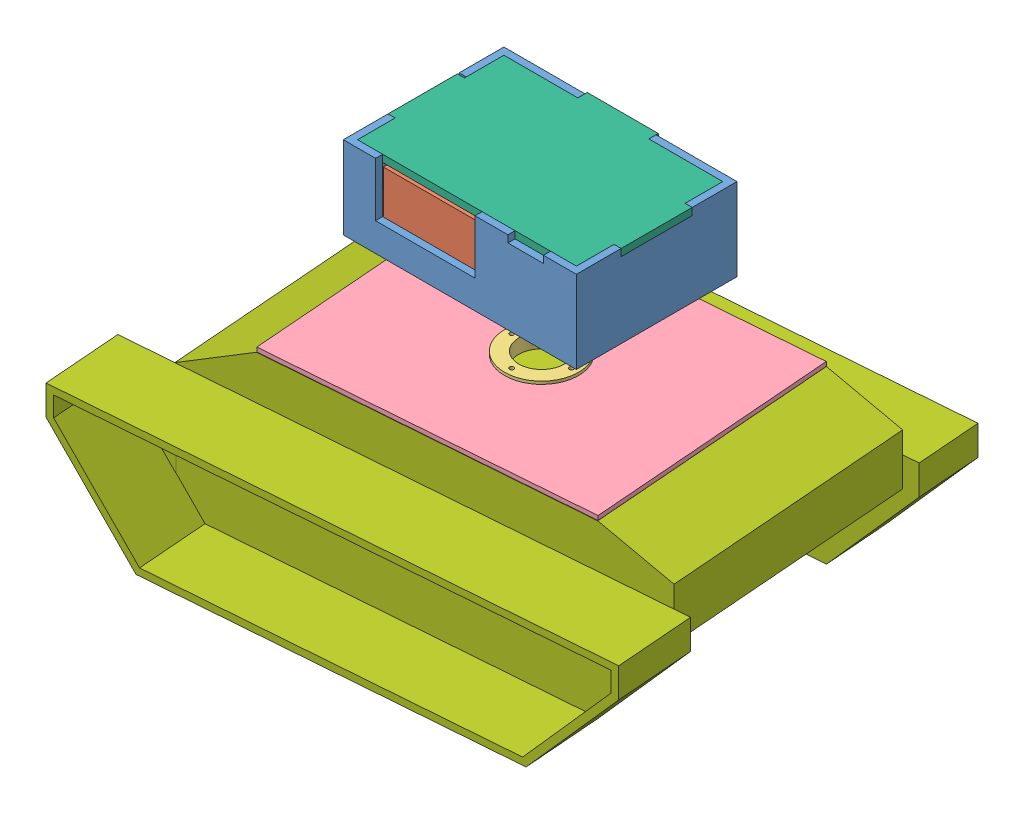
SolidWorks assembly Assemblage1, configuration Default. Lengths in mm.
Overall size (395.2 241.89 303.33).
10 component instances, 7 part files, 23 mates.
Components (placement in the parent):
- boite-1: boite [Default] at (-87.4002 206.352 80.3922) size (164 58 113)
- carte-1: carte [Default] at (-86.4002 223.352 81.6422) size (154 33 101.5)
- fixation-1: fixation [Default] at (-87.4002 137.8761 80.3922) size (70 10 70)
- plaque-1: plaque [Default] at (-87.4002 142.8761 80.3922) x (-0.07779 0 -0.99697) z (0.99697 0 -0.07779) size (174.68 3 223.37)
- entretoise-1: entretoise [Default] at (-17.4002 211.352 37.8922) x (0.957177 0 0.289503) z (-0.289503 0 0.957177) size (8 12 8)
- entretoise-2: entretoise [Default] at (-157.4002 211.352 37.8922) size (8 12 8)
- entretoise-4: entretoise [Default] at (-157.4002 211.352 125.8922) x (0.969192 0 0.246308) z (-0.246308 0 0.969192) size (8 12 8)
- entretoise-5: entretoise [Default] at (-17.4002 211.352 125.8922) x (0.714568 0 -0.699566) z (0.699566 0 0.714568) size (8 12 8)
- plexi haut-1: plexi haut [Default] at (-87.4002 259.352 81.3922) size (164 5 109.63)
- chassis-1: chassis [Default] at (-109.9498 95.7277 -5.4538) x (0.99697 0 -0.07779) z (0.07779 0 0.99697) size (374.95 120.41 275)
Mates (geometry in assembly coordinates):
- Coaxiale1: concentric aligned: cylinder of fixation-1 through (-87.4002 147.8761 80.3922) axis (0 -1 0) radius 26; cylinder of plaque-1 through (-87.4002 145.8761 80.3922) axis (0 -1 0) radius 26
- Coïncidente1: coincident anti-aligned: plane of fixation-1 through (-87.4002 142.8761 80.3922) normal (0 1 0); plane of plaque-1 through (-87.4002 142.8761 80.3922) normal (0 -1 0)
- Coaxiale2: concentric anti-aligned: cylinder of boite-1 through (-87.4002 206.352 80.3922) axis (0 1 0) radius 16; cylinder of fixation-1 through (-87.4002 147.8761 80.3922) axis (0 -1 0) radius 16
- Coïncidente2: coincident aligned: circle of boite-1; cylinder of fixation-1 through (-87.4002 112.8761 59.3922) axis (0 1 0) radius 1.5
- Parallèle1: parallel aligned: cylinder of boite-1 through (-157.4002 206.352 37.8922) axis (0 1 0) radius 1.5; cylinder of carte-1 through (-157.4002 223.352 37.8922) axis (0 1 0) radius 1.5
- Coïncidente3: coincident anti-aligned: plane of carte-1 through (-86.4002 223.352 81.6422) normal (0 -1 0); plane of entretoise-2 through (-157.4002 223.352 37.8922) normal (0 1 0)
- Coaxiale5: concentric anti-aligned: cylinder of carte-1 through (-157.4002 223.352 37.8922) axis (0 1 0) radius 1.5; cylinder of entretoise-2 through (-157.4002 223.352 37.8922) axis (0 -1 0) radius 1.5
- Coaxiale6: concentric anti-aligned: cylinder of carte-1 through (-17.4002 223.352 37.8922) axis (0 1 0) radius 1.5; cylinder of entretoise-1 through (-17.4002 223.352 37.8922) axis (0 -1 0) radius 1.5
- Coïncidente4: coincident anti-aligned: plane of carte-1 through (-86.4002 223.352 81.6422) normal (0 -1 0); plane of entretoise-1 through (-17.4002 223.352 37.8922) normal (0 1 0)
- Coaxiale7: concentric anti-aligned: cylinder of carte-1 through (-157.4002 223.352 125.8922) axis (0 1 0) radius 1.5; cylinder of entretoise-4 through (-157.4002 223.352 125.8922) axis (0 -1 0) radius 1.5
- Coïncidente5: coincident anti-aligned: plane of carte-1 through (-86.4002 223.352 81.6422) normal (0 -1 0); plane of entretoise-4 through (-157.4002 223.352 125.8922) normal (0 1 0)
- Coaxiale8: concentric anti-aligned: cylinder of carte-1 through (-17.4002 223.352 125.8922) axis (0 1 0) radius 1.5; cylinder of entretoise-5 through (-17.4002 223.352 125.8922) axis (0 -1 0) radius 1.5
- Coïncidente6: coincident anti-aligned: plane of carte-1 through (-86.4002 223.352 81.6422) normal (0 -1 0); plane of entretoise-5 through (-17.4002 223.352 125.8922) normal (0 1 0)
- Coaxiale11: concentric anti-aligned: cylinder of boite-1 through (-157.4002 206.352 37.8922) axis (0 1 0) radius 1.5; cylinder of entretoise-2 through (-157.4002 223.352 37.8922) axis (0 -1 0) radius 1.5
- Coaxiale12: concentric anti-aligned: cylinder of boite-1 through (-17.4002 206.352 37.8922) axis (0 1 0) radius 1.5; cylinder of entretoise-1 through (-17.4002 223.352 37.8922) axis (0 -1 0) radius 1.5
- Coaxiale13: concentric anti-aligned: cylinder of boite-1 through (-17.4002 206.352 125.8922) axis (0 1 0) radius 1.5; cylinder of entretoise-5 through (-17.4002 223.352 125.8922) axis (0 -1 0) radius 1.5
- Coïncidente9: coincident anti-aligned: plane of boite-1 through (-87.4002 211.352 80.3922) normal (0 1 0); plane of entretoise-1 through (-17.4002 211.352 37.8922) normal (0 -1 0)
- Coïncidente10: coincident anti-aligned: plane of boite-1 through (-87.4002 259.352 80.3922) normal (0 1 0); plane of plexi haut-1 through (-87.4002 259.352 81.3922) normal (0 -1 0)
- Coïncidente11: coincident aligned: plane of boite-1 through (-5.4002 206.352 24.8922) normal (1 0 0); plane of plexi haut-1 through (-5.4002 264.352 106.3922) normal (1 0 0)
- Coïncidente12: coincident anti-aligned: plane of boite-1 through (-10.4002 259.352 106.3922) normal (0 0 -1); plane of plexi haut-1 through (-10.4002 264.352 106.3922) normal (0 0 1)
- Coïncidente13: coincident anti-aligned: plane of plaque-1 through (-87.4002 142.8761 80.3922) normal (0 -1 0); plane of chassis-1 through (-191.9277 142.8761 176.4745) normal (0 1 0)
- Coïncidente14: coincident: plane of plaque-1 through (17.1522 145.8761 -15.3711) normal (-0.07779 0 -0.99697); line of chassis-1 through (17.2418 142.8761 -15.378) axis (-0.99697 0 0.07779)
- Coïncidente15: coincident anti-aligned: line of plaque-1 through (-205.5409 142.8761 2.0048) axis (0.07779 0 0.99697); line of chassis-1 through (-191.9277 142.8761 176.4745) axis (-0.07779 0 -0.99697)
